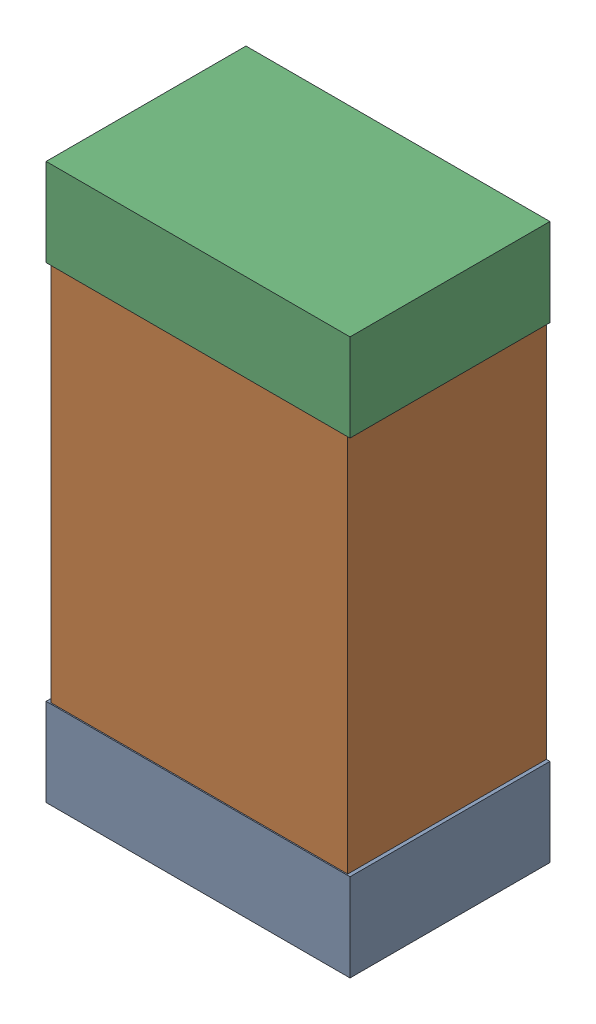
SolidWorks assembly RFBTKanaloa_v2.0.0_Power, configuration Default. Lengths in mm.
Overall size (1.3 2.38 0.85).
6 component instances, 2 part files, 0 mates.
Components (placement in the parent):
- 330415056-1: 330415056 [Default] at (140.1676 51.4565 0) size (1.3 0.38 0.85)
  - Extruded_2-1: Extruded_2 [Default] at origin size (1.3 0.38 0.85)
- 334787376-1: 334787376 [Default] at (140.1676 52.4565 0) size (1.27 2.2 0.85)
  - Extruded_16-1: Extruded_16 [Default] at origin size (1.27 2.2 0.85)
- 330415056-2: 330415056 [Default] at (140.1676 53.4565 0) size (1.3 0.38 0.85)
  - Extruded_2-1: Extruded_2 [Default] at origin size (1.3 0.38 0.85)
